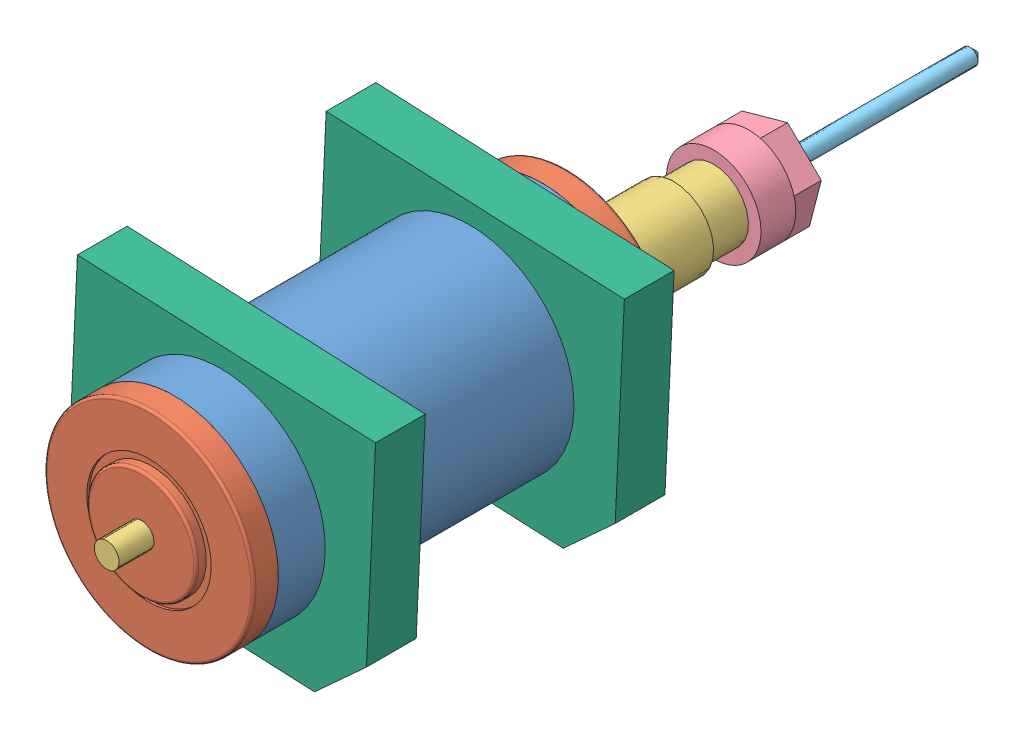
SolidWorks assembly Spindle, configuration Predeterminado. Lengths in mm.
Overall size (62.23 57.81 175).
8 component instances, 6 part files, 10 mates.
Components (placement in the parent):
- cuerpo-1: cuerpo [Predeterminado] at origin size (42 42 74)
- tapa_lado_broca-1: tapa_lado_broca [Predeterminado] x (0.85047 0.526023 0) z (0 0 -1) size (42 42 6.5)
- tapa_lado_broca-2: tapa_lado_broca [Predeterminado] at (0 0 74) x (-0.987096 0.160131 0) z (0 0 1) size (42 42 6.5)
- eje-1: eje [Predeterminado] at (0 0 -47.5) x (0.653715 0.756741 0) z (0.756741 -0.653715 0) size (16 135 16)
- tuerca-1: tuerca [Predeterminado] at (0 0 -34.5) x (-0.923728 -0.383049 0) z (0 0 -1) size (19 19 13)
- broca-1: broca [Predeterminado] at (0 0 -47.5) x (-0.798235 0.602346 0) z (0 0 -1) size (3.25 3.25 40)
- soporte-1: soporte [Predeterminado] at (0 0 4.5749) x (0.99895 -0.045814 0) z (0 0 1) size (60 50 10)
- soporte-2: soporte [Predeterminado] at (0 0 54.5749) x (0.99895 -0.045814 0) z (0 0 1) size (60 50 10)
Mates (geometry in assembly coordinates):
- Coincidente3: coincident anti-aligned: circle of cuerpo-1; circle of tapa_lado_broca-1
- Coincidente4: coincident aligned: circle of cuerpo-1; circle of tapa_lado_broca-2
- Coincidente5: coincident aligned: circle of tapa_lado_broca-1; circle of eje-1
- Coincidente6: coincident aligned: circle of eje-1; circle of tuerca-1
- Concéntrica1: concentric aligned: circle of tuerca-1; circle of broca-1
- Coincidente7: coincident anti-aligned: plane of eje-1 through (0 0 -47.5) normal (0 0 -1); plane of broca-1 through (0 0 -47.5) normal (0 0 1)
- Concéntrica2: concentric aligned: cylinder of cuerpo-1 through (0 0 74) axis (0 0 -1) radius 21; cylinder of soporte-2 through (0 0 64.5749) axis (0 0 -1) radius 21
- Concéntrica3: concentric aligned: cylinder of cuerpo-1 through (0 0 74) axis (0 0 -1) radius 21; cylinder of soporte-1 through (0 0 14.5749) axis (0 0 -1) radius 21
- Paralelo1: parallel aligned: plane of soporte-1 through (31.1139 23.5993 14.5749) normal (0.045814 0.99895 0); plane of soporte-2 through (31.1139 23.5993 64.5749) normal (0.045814 0.99895 0)
- Distancia1: distance = 40 mm anti-aligned: plane of soporte-1 through (0 0 14.5749) normal (0 0 1); plane of soporte-2 through (0 0 54.5749) normal (0 0 -1)
